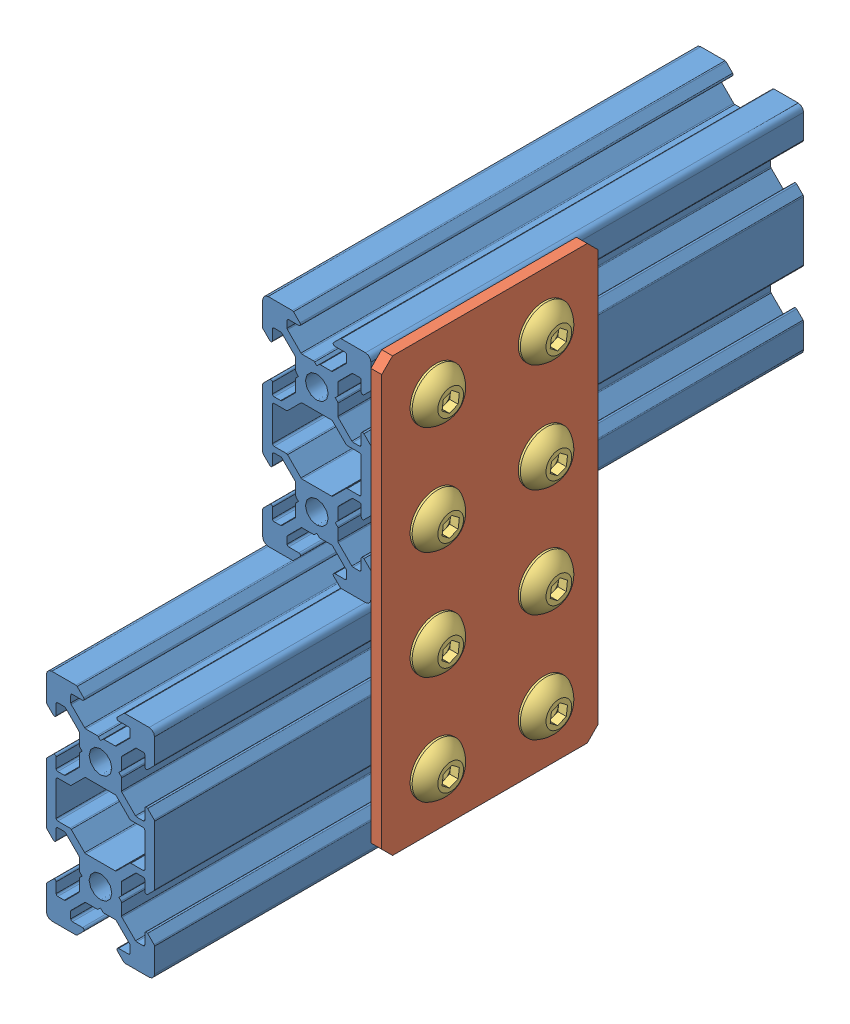
SolidWorks assembly П-Пластина 20 серия 2х4 8отв 40х80х2 СБ, configuration По умолчанию. Lengths in mm.
Overall size (24.75 80 120).
11 component instances, 3 part files, 25 mates.
Components (placement in the parent):
- 204090-1: 204090 [По умолчанию] at (-10 30 -80) x (0 -1 0) z (0 0 1) size (40 20 80)
- 204090-2: 204090 [По умолчанию] at (-10 70 -120) x (0 -1 0) z (0 0 1) size (40 20 80)
- П-Пластина 20 серия 2х4 8отв 40х80х2-1: П-Пластина 20 серия 2х4 8отв 40х80х2 [По умолчанию] at (0 40 -60) x (0 0 -1) z (0 -1 0) size (40 2 80)
- socket button head screw_iso-1: socket button head screw_iso [ISO 7380 - M5 x 10 - 10N] at (4.75 70 -50) x (-1 0 0) z (0 0.924225 0.381849) size (12.75 9.5 9.5)
- socket button head screw_iso-2: socket button head screw_iso [ISO 7380 - M5 x 10 - 10N] at (4.75 70 -70) x (-1 0 0) z (0 0.924225 0.381849) size (12.75 9.5 9.5)
- socket button head screw_iso-3: socket button head screw_iso [ISO 7380 - M5 x 10 - 10N] at (4.75 50 -50) x (-1 0 0) z (0 0.924225 0.381849) size (12.75 9.5 9.5)
- socket button head screw_iso-4: socket button head screw_iso [ISO 7380 - M5 x 10 - 10N] at (4.75 50 -70) x (-1 0 0) z (0 0.924225 0.381849) size (12.75 9.5 9.5)
- socket button head screw_iso-5: socket button head screw_iso [ISO 7380 - M5 x 10 - 10N] at (4.75 30 -50) x (-1 0 0) z (0 0.924225 0.381849) size (12.75 9.5 9.5)
- socket button head screw_iso-6: socket button head screw_iso [ISO 7380 - M5 x 10 - 10N] at (4.75 30 -70) x (-1 0 0) z (0 0.924225 0.381849) size (12.75 9.5 9.5)
- socket button head screw_iso-7: socket button head screw_iso [ISO 7380 - M5 x 10 - 10N] at (4.75 10 -50) x (-1 0 0) z (0 0.924225 0.381849) size (12.75 9.5 9.5)
- socket button head screw_iso-8: socket button head screw_iso [ISO 7380 - M5 x 10 - 10N] at (4.75 10 -70) x (-1 0 0) z (0 0.924225 0.381849) size (12.75 9.5 9.5)
Mates (geometry in assembly coordinates):
- Совпадение1: coincident anti-aligned: plane of 204090-1 through (0 0 0) normal (0 -1 0)
- Совпадение5: coincident aligned: plane of 204090-1 through (-10 30 0) normal (0 0 1)
- Совпадение6: coincident aligned: plane of 204090-1 through (0 14.4 0) normal (1 0 0)
- Совпадение7: coincident anti-aligned: plane of 204090-1 through (0 40 0) normal (0 1 0); plane of 204090-2 through (0 40 -40) normal (0 -1 0)
- Совпадение8: coincident aligned: plane of 204090-1 through (0 40 0) normal (1 0 0); plane of 204090-2 through (0 40 -40) normal (1 0 0)
- Совпадение9: coincident anti-aligned: plane of 204090-1 through (0 14.4 0) normal (1 0 0); plane of П-Пластина 20 серия 2х4 8отв 40х80х2-1 through (0 40 -60) normal (-1 0 0)
- Совпадение10: coincident aligned: plane of 204090-1 through (0 0 0) normal (0 -1 0); plane of П-Пластина 20 серия 2х4 8отв 40х80х2-1 through (2 0 -40) normal (0 -1 0)
- Совпадение11: coincident aligned: plane of 204090-2 through (-10 70 -40) normal (0 0 1); plane of П-Пластина 20 серия 2х4 8отв 40х80х2-1 through (2 0 -40) normal (0 0 1)
- Совпадение12: coincident aligned: plane of 204090-1 through (-10 30 -80) normal (0 0 -1); plane of П-Пластина 20 серия 2х4 8отв 40х80х2-1 through (2 0 -80) normal (0 0 -1)
- Концентричный1: concentric aligned: cylinder of П-Пластина 20 серия 2х4 8отв 40х80х2-1 through (2 70 -50) axis (1 0 0) radius 2.75; cylinder of socket button head screw_iso-1 through (4.75 70 -50) axis (1 0 0) radius 4.75
- Совпадение13: coincident anti-aligned: plane of П-Пластина 20 серия 2х4 8отв 40х80х2-1 through (2 40 -60) normal (1 0 0); plane of socket button head screw_iso-1 through (2 69.0454 -47.6894) normal (-1 0 0)
- Концентричный2: concentric aligned: cylinder of П-Пластина 20 серия 2х4 8отв 40х80х2-1 through (2 70 -70) axis (1 0 0) radius 2.75; cylinder of socket button head screw_iso-2 through (4.75 70 -70) axis (1 0 0) radius 4.75
- Совпадение14: coincident anti-aligned: plane of П-Пластина 20 серия 2х4 8отв 40х80х2-1 through (2 40 -60) normal (1 0 0); plane of socket button head screw_iso-2 through (2 69.0454 -67.6894) normal (-1 0 0)
- Концентричный3: concentric aligned: cylinder of П-Пластина 20 серия 2х4 8отв 40х80х2-1 through (2 50 -50) axis (1 0 0) radius 2.75; cylinder of socket button head screw_iso-3 through (4.75 50 -50) axis (1 0 0) radius 4.75
- Совпадение15: coincident anti-aligned: plane of П-Пластина 20 серия 2х4 8отв 40х80х2-1 through (2 40 -60) normal (1 0 0); plane of socket button head screw_iso-3 through (2 49.0454 -47.6894) normal (-1 0 0)
- Концентричный4: concentric aligned: cylinder of П-Пластина 20 серия 2х4 8отв 40х80х2-1 through (2 50 -70) axis (1 0 0) radius 2.75; cylinder of socket button head screw_iso-4 through (4.75 50 -70) axis (1 0 0) radius 4.75
- Совпадение16: coincident anti-aligned: plane of П-Пластина 20 серия 2х4 8отв 40х80х2-1 through (2 40 -60) normal (1 0 0); plane of socket button head screw_iso-4 through (2 49.0454 -67.6894) normal (-1 0 0)
- Концентричный5: concentric aligned: cylinder of П-Пластина 20 серия 2х4 8отв 40х80х2-1 through (2 30 -50) axis (1 0 0) radius 2.75; cylinder of socket button head screw_iso-5 through (4.75 30 -50) axis (1 0 0) radius 4.75
- Совпадение17: coincident anti-aligned: plane of П-Пластина 20 серия 2х4 8отв 40х80х2-1 through (2 40 -60) normal (1 0 0); plane of socket button head screw_iso-5 through (2 29.0454 -47.6894) normal (-1 0 0)
- Концентричный6: concentric aligned: cylinder of П-Пластина 20 серия 2х4 8отв 40х80х2-1 through (2 30 -70) axis (1 0 0) radius 2.75; cylinder of socket button head screw_iso-6 through (4.75 30 -70) axis (1 0 0) radius 4.75
- Совпадение18: coincident anti-aligned: plane of П-Пластина 20 серия 2х4 8отв 40х80х2-1 through (2 40 -60) normal (1 0 0); plane of socket button head screw_iso-6 through (2 29.0454 -67.6894) normal (-1 0 0)
- Концентричный7: concentric aligned: cylinder of П-Пластина 20 серия 2х4 8отв 40х80х2-1 through (2 10 -50) axis (1 0 0) radius 2.75; cylinder of socket button head screw_iso-7 through (4.75 10 -50) axis (1 0 0) radius 4.75
- Совпадение19: coincident anti-aligned: plane of П-Пластина 20 серия 2х4 8отв 40х80х2-1 through (2 40 -60) normal (1 0 0); plane of socket button head screw_iso-7 through (2 9.0454 -47.6894) normal (-1 0 0)
- Концентричный8: concentric aligned: cylinder of П-Пластина 20 серия 2х4 8отв 40х80х2-1 through (2 10 -70) axis (1 0 0) radius 2.75; cylinder of socket button head screw_iso-8 through (4.75 10 -70) axis (1 0 0) radius 4.75
- Совпадение20: coincident anti-aligned: plane of П-Пластина 20 серия 2х4 8отв 40х80х2-1 through (2 40 -60) normal (1 0 0); plane of socket button head screw_iso-8 through (2 9.0454 -67.6894) normal (-1 0 0)
